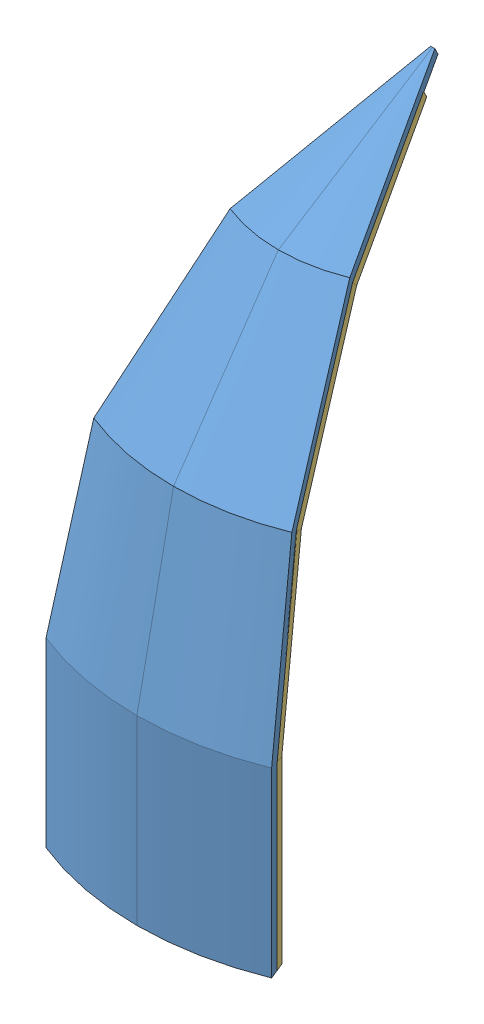
SolidWorks assembly Assem2, configuration Default. Lengths in mm.
Overall size (1118.52 3015.97 1585.48).
8 component instances, 3 part files, 3 mates.
Components (placement in the parent):
- Assem1-1: Assem1 [Default] at (1342.637 -336.3175 -481.3214) size (563.93 3015.97 1482.16)
  - Part1-1: Part1 [Default] at (643.5811 535.4134 3088.0664) size (555.23 3015.97 1482.16)
  - steel 1-1: steel 1 [Default] at (103.5995 535.4134 2992.4104) x (0.927184 0 0.374607) z (-0.374607 0 0.927184) size (50 2898.58 1340.95)
  - steel 2-1: steel 2 [Default] at (643.5811 535.4134 3097.3722) x (0 0 -1) z (1 0 0) size (1340.95 2898.58 50)
- Assem1-2: Assem1 [Default] at (769.1857 -336.3175 -119.6547) x (0.927184 0 -0.374607) z (0.374607 0 0.927184) size (563.93 3015.97 1482.16)
  - Part1-1: Part1 [Default] at (643.5811 535.4134 3088.0664) size (555.23 3015.97 1482.16)
  - steel 1-1: steel 1 [Default] at (103.5995 535.4134 2992.4104) x (0.927184 0 0.374607) z (-0.374607 0 0.927184) size (50 2898.58 1340.95)
  - steel 2-1: steel 2 [Default] at (643.5811 535.4134 3097.3722) x (0 0 -1) z (1 0 0) size (1340.95 2898.58 50)
Mates (geometry in assembly coordinates):
- Coincident1: coincident aligned: plane of Assem1-1/Part1-1 through (1986.2182 199.096 1174.5876) normal (0 -1 0); plane of Assem1-2/Part1-1 through (1986.2182 199.096 1174.5876) normal (0 -1 0)
- Coincident4: coincident anti-aligned: plane of Assem1-1/steel 2-1 through (1986.2182 2453.8927 1701.9656) normal (1 0 0); plane of Assem1-2/steel 1-1 through (1986.2182 2453.8927 1701.9656) normal (-1 0 0)
- Coincident5: coincident aligned: line of Assem1-1/steel 2-1 through (1986.2182 199.096 2566.0508) axis (-1 0 0); line of Assem1-2/steel 1-1 through (1991.2182 199.096 2566.0508) axis (-1 0 0)
